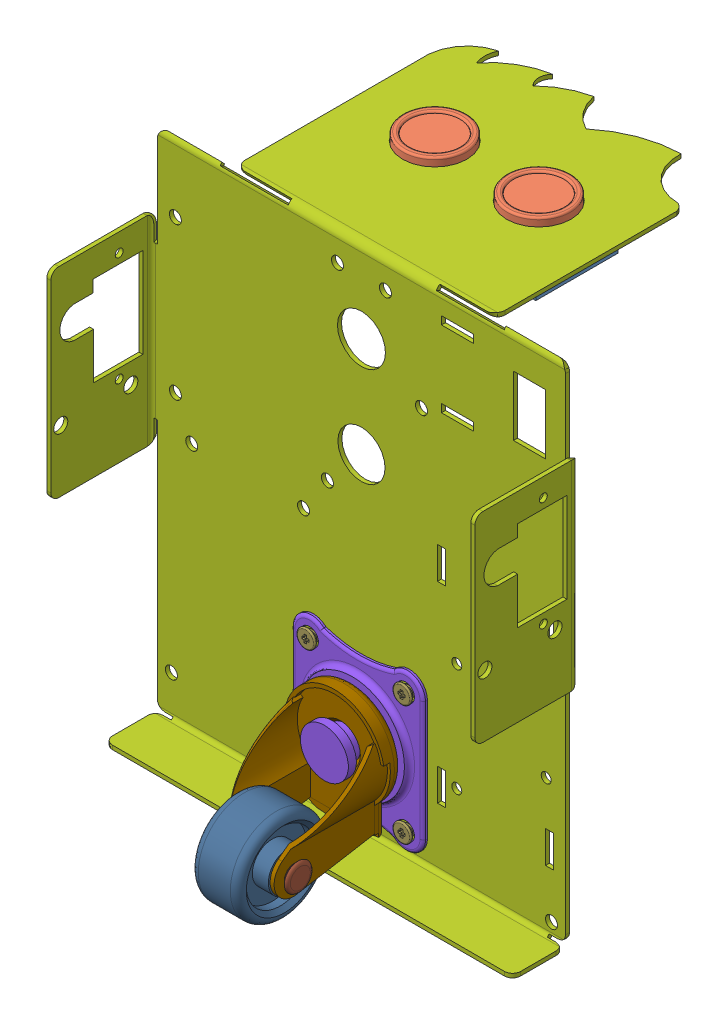
SolidWorks assembly MS, configuration Predeterminado. Lengths in mm.
Overall size (107.01 134.15 98.35).
26 component instances, 12 part files, 7 mates.
Components (placement in the parent):
- HC-SR04 Ping Sensor-1: HC-SR04 Ping Sensor [Default] at (151.0972 -203.6208 108.4775) x (0 0 -1) z (0 1 0) size (25.18 45 18.07)
  - PCB-1: PCB [Default] at origin size (20.5 45 1.75)
  - Transducer-1: Transducer [Default] at (0 -13 13.25) x (1 0 0) z (0 -1 0) size (15.88 12 15.88)
  - Transducer-2: Transducer [Default] at (0 13 13.25) x (1 0 0) z (0 -1 0) size (15.88 12 15.88)
  - 3 Pin Header 90 Degree-1: 3 Pin Header 90 Degree [Default] at (8.4275 0 -1.25) x (-1 0 0) z (0 -1 0) size (8 7.82 10)
  - 14 Pin SMT-1: 14 Pin SMT [Default] at (-0.35 -18.5 -0.85) x (0 -1 0) z (1 0 0) size (6 1.6 8.8)
  - 14 Pin SMT-2: 14 Pin SMT [Default] at (0 -0.3826 -0.85) x (1 0 0) z (0 1 0) size (6 1.6 8.8)
  - 14 Pin SMT-3: 14 Pin SMT [Default] at (0 17.5274 -0.85) x (1 0 0) z (0 1 0) size (6 1.6 8.8)
  - Cap1 SMT-1: Cap1 SMT [Default] at (-1.755 7.4774 -0.9689) x (0 1 0) z (-1 0 0) size (4.5 1.84 1.75)
  - Cap1 SMT-2: Cap1 SMT [Default] at (6.835 7.4774 -0.9689) x (0 1 0) z (-1 0 0) size (4.5 1.84 1.75)
  - Cap1 SMT-3: Cap1 SMT [Default] at (-6.835 7.4774 -0.9689) x (0 1 0) z (-1 0 0) size (4.5 1.84 1.75)
  - Cap1 SMT-4: Cap1 SMT [Default] at (4.295 7.4774 -0.9689) x (0 1 0) z (-1 0 0) size (4.5 1.84 1.75)
  - Cap1 SMT-5: Cap1 SMT [Default] at (1.755 7.4774 -0.9689) x (0 1 0) z (-1 0 0) size (4.5 1.84 1.75)
  - Cap1 SMT-6: Cap1 SMT [Default] at (-4.295 7.4774 -0.9689) x (0 1 0) z (-1 0 0) size (4.5 1.84 1.75)
  - HC-SR04 Crystal-1: HC-SR04 Crystal [Default] at (-8.3 0 1.75) x (0 -1 0) z (0 0 1) size (10 3.5 2.7)
- DYOR_MetalSheet-1: DYOR_MetalSheet [Predeterminado] at (90.3982 -139.1144 139.7994) size (107.01 127.54 85.91)
- CA-1: CA [Predeterminado] at (2.8826 1.8185 1.124) size (33 45.94 42.59)
  - Caster Wheel-1: Caster Wheel [Default] at (194.2283 -297.83 183.8938) x (0 1 0) z (-1 0 0) size (45.94 37.59 33)
    - caster holder-1: caster holder [Default] at (-24.0751 44.7184 29.5137) x (1 0 0) z (0 0 -1) size (39 9.27 33)
    - holder-1: holder [Default] at (-1.5751 42.9484 46.0137) x (0 0 1) z (1 0 0) size (25 28.07 31.31)
    - caster wheel-1: caster wheel [Default] at (-15.6961 19.9484 46.0137) x (0.997275 0.073773 0) z (0 0 1) size (23 23 14)
    - Part4-1: Part4 [Default] at (-15.6961 19.9484 55.0137) x (-0.978448 0.206495 0) z (0 0 -1) size (7 7 20)
  - M3x6 SelfTap Screw-1: M3x6 SelfTap Screw [Predeterminado] at (136.2146 -284.4051 140.6754) size (4.62 4.62 7)
  - M3x6 SelfTap Screw-2: M3x6 SelfTap Screw [Predeterminado] at (136.2146 -314.4051 140.6754) size (4.62 4.62 7)
  - M3x6 SelfTap Screw-3: M3x6 SelfTap Screw [Predeterminado] at (160.2146 -284.4051 140.6754) size (4.62 4.62 7)
  - M3x6 SelfTap Screw-4: M3x6 SelfTap Screw [Predeterminado] at (160.2146 -314.4051 140.6754) size (4.62 4.62 7)
Mates (geometry in assembly coordinates):
- Concéntrica258: concentric: circle of HC-SR04 Ping Sensor-1/Transducer-1; circle of DYOR_MetalSheet-1
- Concéntrica289: concentric: circle of DYOR_MetalSheet-1; circle of ?
- Concéntrica290: concentric: circle of DYOR_MetalSheet-1; circle of ?
- Paralelo1: parallel: plane of HC-SR04 Ping Sensor-1/PCB-1 through (128.5972 -201.8708 98.2275) normal (0 0 -1); plane of DYOR_MetalSheet-1 through (120.6083 -190.1666 138.7994) normal (0 0 -1)
- Distancia1: distance = 2 mm: plane of HC-SR04 Ping Sensor-1/Transducer-1 through (164.0972 -189.8708 100.5375) normal (0 1 0); plane of DYOR_MetalSheet-1 through (120.6083 -191.8708 136.4514) normal (0 1 0)
- Coincidente488: coincident: plane of DYOR_MetalSheet-1 through (120.6083 -190.1666 139.7994) normal (0 0 1); plane of CA-1/Caster Wheel-1/caster holder-1 through (151.0972 -252.7884 139.7994) normal (0 0 -1)
- Concéntrica291: concentric: circle of DYOR_MetalSheet-1; circle of CA-1/Caster Wheel-1/caster holder-1
